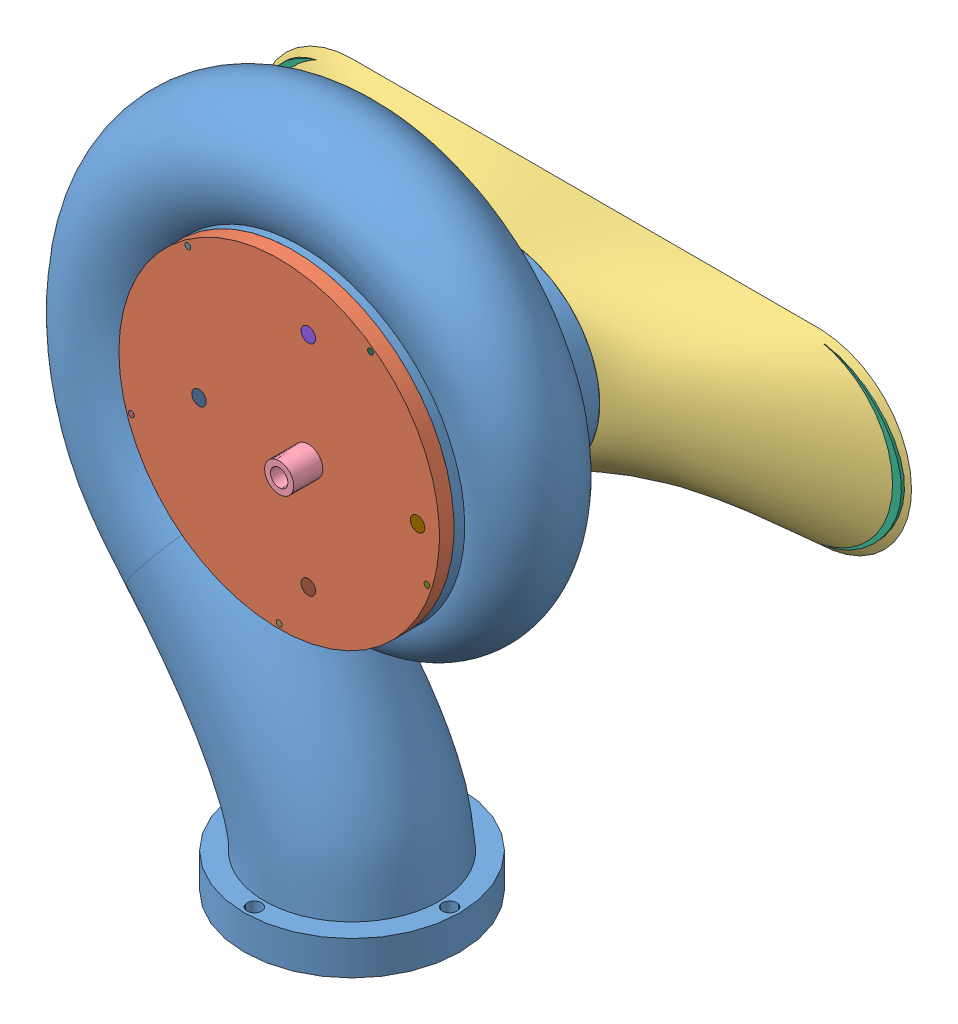
SolidWorks assembly Simulation Centrifugal Pump Assembly, configuration Default. Lengths in mm.
Overall size (112.76 116.74 53.6).
21 component instances, 21 part files, 9 mates.
Components (placement in the parent):
- Simulation Centrifugal Pump Casing-1: Simulation Centrifugal Pump Casing [Default] at (16.7614 68.1112 112.1618) x (1 0 0) z (0 0 -1) size (87.32 116.73 39.5)
- Simulation Centrifugal Pump Casing Cover-1: Simulation Centrifugal Pump Casing Cover [Default] at (16.7614 68.1112 123.4118) x (1 0 0) z (0 0 -1) size (55 55 2.5)
- Simulation Centrifugal Pump Casing Extension-1: Simulation Centrifugal Pump Casing Extension [Default] at (21.7614 68.1112 77.1618) size (112.11 33.02 14.11)
- Simulation Centrifugal Pump Impeller-1: Simulation Centrifugal Pump Impeller [Default] at (21.7614 68.1112 117.8285) x (0.461828 -0.886969 0) z (0 0 -1) size (52 52 22.83)
- Simulation Fluid Region-1: Simulation Fluid Region [Default] at (21.7614 68.1112 106.8285) size (52 52 11)
- LID17-1: LID17 [Default] at origin size (111.87 30.28 0.91)
- LID18-1: LID18 [Default] at origin size (3.09 3.09 0.86)
- LID19-1: LID19 [Default] at origin size (2.58 2.58 0.86)
- LID20-1: LID20 [Default] at origin size (2.58 2.58 0.86)
- LID21-1: LID21 [Default] at origin size (2.58 2.58 0.86)
- LID22-1: LID22 [Default] at origin size (2.58 2.58 0.86)
- LID23-1: LID23 [Default] at origin size (1.04 1.04 0.86)
- LID24-1: LID24 [Default] at origin size (1.04 1.04 0.86)
- LID25-1: LID25 [Default] at origin size (1.04 1.04 0.86)
- LID26-1: LID26 [Default] at origin size (1.04 1.04 0.86)
- LID27-1: LID27 [Default] at origin size (1.04 1.04 0.86)
- LID28-1: LID28 [Default] at origin size (28.8 0.86 28.8)
- LID29-1: LID29 [Default] at origin size (2.58 0.86 2.58)
- LID30-1: LID30 [Default] at origin size (2.58 0.86 2.58)
- LID31-1: LID31 [Default] at origin size (2.58 0.86 2.58)
- LID32-1: LID32 [Default] at origin size (2.58 0.86 2.58)
Mates (geometry in assembly coordinates):
- Coincident2: coincident anti-aligned: circle of Simulation Centrifugal Pump Casing-1; circle of Simulation Centrifugal Pump Casing Extension-1
- Parallel2: parallel: line of Simulation Centrifugal Pump Casing Extension-1 through (-18.2386 52.1112 77.1618) axis (1 0 0)
- Concentric5: concentric aligned: cylinder of Simulation Centrifugal Pump Casing-1 through (16.7614 68.1112 102.1618) axis (0 0 1) radius 27.5; cylinder of Simulation Centrifugal Pump Casing Cover-1 through (16.7614 68.1112 122.1618) axis (0 0 1) radius 27.5
- Coincident7: coincident anti-aligned: plane of Simulation Centrifugal Pump Casing-1 through (16.7614 68.1112 122.1618) normal (0 0 1); plane of Simulation Centrifugal Pump Casing Cover-1 through (16.7614 68.1112 122.1618) normal (0 0 -1)
- Concentric6: concentric anti-aligned: cylinder of Simulation Centrifugal Pump Casing-1 through (42.123 59.8707 122.1618) axis (0 0 1) radius 0.5; cylinder of Simulation Centrifugal Pump Casing Cover-1 through (42.123 59.8708 122.1618) axis (0 0 -1) radius 0.5
- Concentric7: concentric aligned: cylinder of Simulation Centrifugal Pump Impeller-1 through (21.7614 68.1112 107.8285) axis (0 0 -1) radius 26; cylinder of Simulation Fluid Region-1 through (21.7614 68.1112 117.8285) axis (0 0 -1) radius 26
- Coincident8: coincident aligned: plane of Simulation Centrifugal Pump Impeller-1 through (21.7614 68.1112 117.8285) normal (0 0 1); plane of Simulation Fluid Region-1 through (21.7614 68.1112 117.8285) normal (0 0 1)
- Concentric8: concentric aligned: cylinder of Simulation Centrifugal Pump Casing Cover-1 through (21.7614 68.1112 124.6618) axis (0 0 -1) radius 2.5; cylinder of Simulation Centrifugal Pump Impeller-1 through (21.7614 68.1112 129.6618) axis (0 0 -1) radius 2.5
- Distance1: distance = 4.3333 mm anti-aligned: plane of Simulation Centrifugal Pump Impeller-1 through (21.7614 68.1112 117.8285) normal (0 0 1); plane of Simulation Centrifugal Pump Casing Cover-1 through (16.7614 68.1112 122.1618) normal (0 0 -1)
